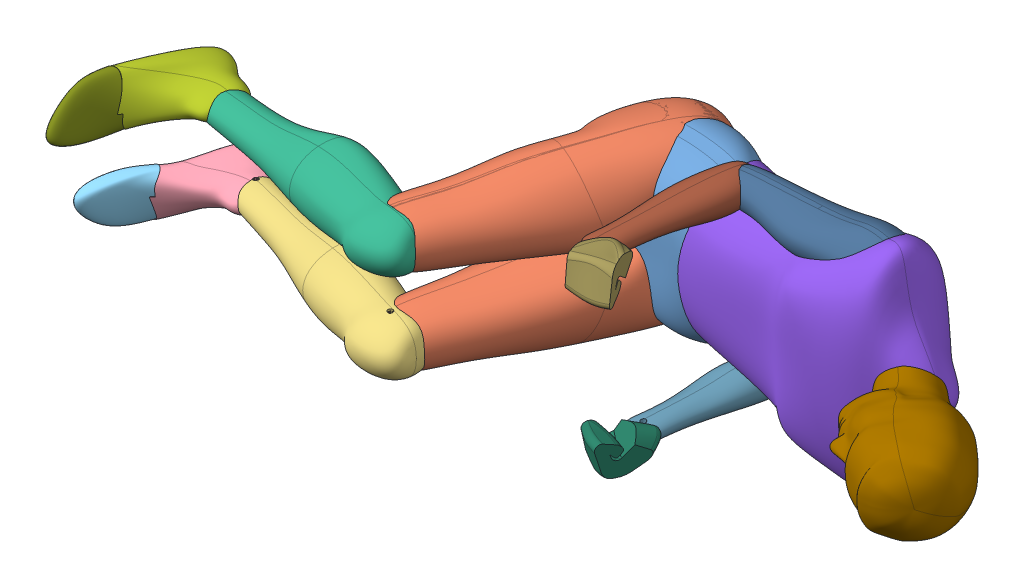
SolidWorks assembly man, configuration Default. Lengths in mm.
Overall size (1556.2 471.37 952.11).
17 component instances, 16 part files, 46 mates.
Components (placement in the parent):
- pelvis-1: pelvis [Default] at (32.77 0 0) x (0 -1 0) z (1 0 0) size (400 212.17 283.31)
- r_thigh-2: r_thigh [левый] at (13.2448 0 -26.5178) x (0 -1 0) z (0.296897 0 -0.954909) size (336.52 246.68 623.17)
- Mirrorr_calf-2: Mirrorr_calf [Default] at (319.2731 0 530.603) x (0 -1 0) z (0.97254 0 0.232736) size (127.01 156.16 503.94)
- Mirrorr_foot-1: Mirrorr_foot [Default] at (259.9428 0 685.3038) x (0 -1 0) z (0.918341 0 0.39579) size (107.05 328.32 124.15)
- Mirrorr_toe-1: Mirrorr_toe [Default] at (281.5181 0 605.2298) x (0 -1 0) z (0.949342 0 0.314246) size (103.98 198.17 49.25)
- r_thigh-1: r_thigh [Default] at (13.6841 0 -26.3772) x (0 -1 0) z (0.312716 0 -0.949847) size (222.9 246.68 623.17)
- r_calf_new-1: r_calf_new [Default] at (323.6478 0 467.5909) x (0 -1 0) z (0.994791 0 0.101933) size (127.01 156.16 503.94)
- r_foot-1: r_foot [Default] at (304.3353 0 565.9297) x (0 -1 0) z (0.980232 0 0.19785) size (174.64 328.32 967.15)
- torso-1: torso [Default] at (35.6631 0 -19.1834) x (0 -1 0) z (0.984808 0 0.173648) size (471.37 345.34 646.55)
- head-1: head [Default] at (135.2432 0 -258.2437) x (0 -1 0) z (0.766044 0 0.642788) size (182.14 196.78 355.07)
- r_uprarm-1: r_uprarm [Default] at (35.7015 -25 91.994) x (0 -1 0) z (0.996797 0 -0.079972) size (101.79 125.62 366.77)
- r_forearm-1: r_forearm [Default] at (210.6784 -25 230.4513) x (0 -1 0) z (0.108421 0 -0.994105) size (68.37 88.83 304.6)
- r_hand-1: r_hand [Default] at (169.3319 -25 225.9251) x (0 -1 0) z (-0.410559 0 -0.911834) size (75.14 72.73 123.15)
- l_uprarm-1: l_uprarm [Default] at (38.8764 25 -40.2593) x (0 -1 0) z (0.975188 0 0.221377) size (101.79 125.62 366.77)
- l_forearm-1: l_forearm [Default] at (214.7269 25 151.0264) x (0 -1 0) z (0.121071 0 -0.992644) size (68.37 88.83 304.6)
- l_hand-1: l_hand [Default] at (229.3952 25 158.9068) x (0 -1 0) z (0.326045 0 -0.945354) size (75.14 72.73 123.15)
- r_toe-1: r_toe [Default] at (308.9296 0 483.1273) x (0 -1 0) z (0.993746 0 0.111665) size (103.98 198.17 49.25)
Mates (geometry in assembly coordinates):
- Distance3: distance = 0 mm: line of pelvis-1 through (5 111.08 0) axis (0 -1 0); plane of assembly
- Coincident7: coincident: plane of pelvis-1 through (32.77 0 0) normal (0 -1 0); plane of assembly through (0 0 0) normal (0 1 0)
- Distance4: distance = 5 mm: line of pelvis-1 through (5 111.08 0) axis (0 -1 0); plane of assembly
- Angle1: planar angle = 3.141593 rad: plane of pelvis-1 through (32.77 0 0) normal (0 0 -1); plane of assembly through (0 0 0) normal (0 0 1)
- Concentric1: concentric: cylinder of pelvis-1 through (5 -164.1489 0) axis (0 1 0) radius 5; cylinder of r_thigh-2 through (5 -111.08 0) axis (0 1 0) radius 5
- Coincident17: coincident: plane of r_thigh-2 through (5 -111.08 0) normal (0 1 0); plane of pelvis-1 through (5 -111.08 0) normal (0 -1 0)
- Angle3: planar angle = 6.195919 rad: plane of Mirrorr_foot-1 through (259.9428 0 685.3038) normal (0.918341 0 0.39579); plane of Mirrorr_toe-1 through (281.5181 0 605.2298) normal (0.949342 0 0.314246)
- Concentric6: concentric: cylinder of pelvis-1 through (5 164.7498 0) axis (0 -1 0) radius 5; cylinder of r_thigh-1 through (5 111.08 0) axis (0 -1 0) radius 5
- Coincident26: coincident: plane of pelvis-1 through (5 111.08 0) normal (0 1 0); plane of r_thigh-1 through (5 111.08 0) normal (0 -1 0)
- Concentric7: concentric: cylinder of r_thigh-1 through (-138.3692 90.2525 413.2705) axis (0 -1 0) radius 5; cylinder of r_calf_new-1 through (-138.3692 90.2525 413.2705) axis (0 -1 0) radius 5
- Coincident27: coincident: plane of r_thigh-1 through (-138.3692 90.2525 413.2705) normal (0 -1 0); plane of r_calf_new-1 through (-138.3692 90.2525 413.2705) normal (0 -1 0)
- Concentric8: concentric: cylinder of r_foot-1 through (-543.0125 90.2525 343.8925) axis (0 -1 0) radius 5; cylinder of r_calf_new-1 through (-543.0125 90.2525 343.8925) axis (0 -1 0) radius 5
- Coincident28: coincident: plane of r_calf_new-1 through (-543.0125 90.2525 343.8925) normal (0 -1 0); plane of r_foot-1 through (-543.0125 90.2525 343.8925) normal (0 -1 0)
- Angle5: planar angle = 6.108652 rad: plane of pelvis-1 through (32.77 0 0) normal (0 0 -1); plane of torso-1 through (35.6631 0 -19.1834) normal (0.173648 0 -0.984808)
- Coincident31: coincident: plane of pelvis-1 through (32.77 0 0) normal (0 -1 0); plane of torso-1 through (35.6631 0 -19.1834) normal (0 -1 0)
- Coincident32: coincident: point of torso-1; point of pelvis-1
- Angle7: planar angle = 0.523599 rad: plane of torso-1 through (35.6631 0 -19.1834) normal (0.173648 0 -0.984808); plane of head-1 through (135.2432 0 -258.2437) normal (0.642788 0 -0.766044)
- Coincident33: coincident: plane of torso-1 through (35.6631 0 -19.1834) normal (0 -1 0); plane of head-1 through (135.2432 0 -258.2437) normal (0 -1 0)
- Coincident34: coincident: point of torso-1; point of head-1
- Concentric10: concentric: cylinder of torso-1 through (470.0128 236.4376 36.2554) axis (0 -1 0) radius 5; cylinder of r_uprarm-1 through (470.0128 169.39 36.2554) axis (0 -1 0) radius 5
- Distance7: distance = 25 mm: plane of torso-1 through (470.0128 194.39 36.2554) normal (0 1 0); plane of r_uprarm-1 through (470.0128 169.39 36.2554) normal (0 -1 0)
- Coincident36: coincident: axis of r_uprarm-1 through (206.8898 178.8376 55.4462) axis (0 -1 0); axis of r_forearm-1 through (206.8898 178.8376 55.4462) axis (0 -1 0)
- Coincident37: coincident: plane of r_uprarm-1 through (206.8898 178.8376 55.4462) normal (0 -1 0); plane of r_forearm-1 through (206.8898 178.8376 55.4462) normal (0 -1 0)
- Concentric11: concentric: cylinder of r_forearm-1 through (181.6939 178.9768 304.1102) axis (0 -1 0) radius 5; cylinder of r_hand-1 through (181.6939 178.9768 304.1102) axis (0 -1 0) radius 5
- Coincident38: coincident: plane of r_forearm-1 through (181.6939 178.9768 304.1102) normal (0 -1 0); plane of r_hand-1 through (181.6939 178.9768 304.1102) normal (0 -1 0)
- Concentric12: concentric: cylinder of torso-1 through (470.0128 -234.9127 36.2554) axis (0 1 0) radius 5; cylinder of l_uprarm-1 through (470.0128 -169.39 36.2554) axis (0 1 0) radius 5
- Distance6: distance = 25 mm: plane of torso-1 through (470.0128 -194.39 36.2554) normal (0 -1 0); plane of l_uprarm-1 through (470.0128 -169.39 36.2554) normal (0 1 0)
- Concentric13: concentric: cylinder of l_uprarm-1 through (213.167 -178.8376 -24.0129) axis (0 1 0) radius 5; cylinder of l_forearm-1 through (213.167 -178.8376 -24.0129) axis (0 1 0) radius 5
- Coincident40: coincident: plane of l_uprarm-1 through (213.167 -178.8376 -24.0129) normal (0 1 0); plane of l_forearm-1 through (213.167 -178.8376 -24.0129) normal (0 1 0)
- Concentric14: concentric: cylinder of l_forearm-1 through (184.8067 -178.9768 224.3102) axis (0 1 0) radius 5; cylinder of l_hand-1 through (184.8067 -178.9768 224.3102) axis (0 1 0) radius 5
- Coincident41: coincident: plane of l_forearm-1 through (184.8067 -178.9768 224.3102) normal (0 1 0); plane of l_hand-1 through (184.8067 -178.9768 224.3102) normal (0 1 0)
- Concentric15: concentric: cylinder of r_toe-1 through (-641.6109 90.2525 471.9155) axis (0 1 0) radius 20; cylinder of r_foot-1 through (-641.6109 90.2525 471.9155) axis (0 1 0) radius 20
- Coincident42: coincident: plane of r_toe-1 through (-641.6109 90.2525 471.9155) normal (0 1 0); plane of r_foot-1 through (-641.6109 90.2525 471.9155) normal (0 -1 0)
- Angle9: planar angle = 6.195919 rad: plane of r_foot-1 through (304.3353 0 565.9297) normal (0.980232 0 0.19785); plane of r_toe-1 through (308.9296 0 483.1273) normal (0.993746 0 0.111665)
- LimitAngle2: limit planar angle = 1.742835 rad: plane of Mirrorr_calf-2 through (319.2731 0 530.603) normal (0.232736 0 -0.97254); plane of Mirrorr_foot-1 through (259.9428 0 685.3038) normal (0.918341 0 0.39579)
- LimitAngle6: limit planar angle = 1.66785 rad: plane of r_foot-1 through (304.3353 0 565.9297) normal (0.19785 0 -0.980232); plane of r_calf_new-1 through (323.6478 0 467.5909) normal (0.994791 0 0.101933)
- LimitAngle3: limit planar angle = 1.269355 rad: plane of pelvis-1 through (32.77 0 0) normal (0 0 -1); plane of r_thigh-2 through (13.2448 0 -26.5178) normal (-0.954909 0 -0.296897)
- LimitAngle4: limit planar angle = 1.252745 rad: plane of pelvis-1 through (32.77 0 0) normal (0 0 -1); plane of r_thigh-1 through (13.6841 0 -26.3772) normal (-0.949847 0 -0.312716)
- LimitAngle5: limit planar angle = 1.354856 rad: plane of r_thigh-1 through (13.6841 0 -26.3772) normal (-0.949847 0 -0.312716); plane of r_calf_new-1 through (323.6478 0 467.5909) normal (0.101933 0 -0.994791)
- LimitAngle1: limit planar angle = 1.504244 rad: plane of r_thigh-2 through (13.2448 0 -26.5178) normal (-0.954909 0 -0.296897); plane of Mirrorr_calf-2 through (319.2731 0 530.603) normal (0.232736 0 -0.97254)
- Concentric16: concentric: cylinder of Mirrorr_calf-2 through (-131.4857 -90.2525 415.5947) axis (0 1 0) radius 5; cylinder of r_thigh-2 through (-131.4857 -90.2525 415.5947) axis (0 1 0) radius 5
- Coincident43: coincident: plane of r_thigh-2 through (-131.4857 -90.2525 415.5947) normal (0 1 0); plane of Mirrorr_calf-2 through (-131.4857 -90.2525 415.5947) normal (0 1 0)
- Concentric17: concentric: cylinder of Mirrorr_calf-2 through (-523.3823 -90.2525 293.257) axis (0 1 0) radius 5; cylinder of Mirrorr_foot-1 through (-523.3823 -90.2525 293.257) axis (0 1 0) radius 5
- Coincident44: coincident: plane of Mirrorr_calf-2 through (-523.3823 -90.2525 293.257) normal (0 1 0); plane of Mirrorr_foot-1 through (-523.3823 -90.2525 293.257) normal (0 1 0)
- Concentric18: concentric: cylinder of Mirrorr_foot-1 through (-646.268 -90.2525 398.1886) axis (0 1 0) radius 25; cylinder of Mirrorr_toe-1 through (-646.268 -90.2525 398.1886) axis (0 1 0) radius 25
- Coincident45: coincident: plane of Mirrorr_foot-1 through (-646.268 -90.2525 398.1886) normal (0 1 0); plane of Mirrorr_toe-1 through (-646.268 -90.2525 398.1886) normal (0 -1 0)
